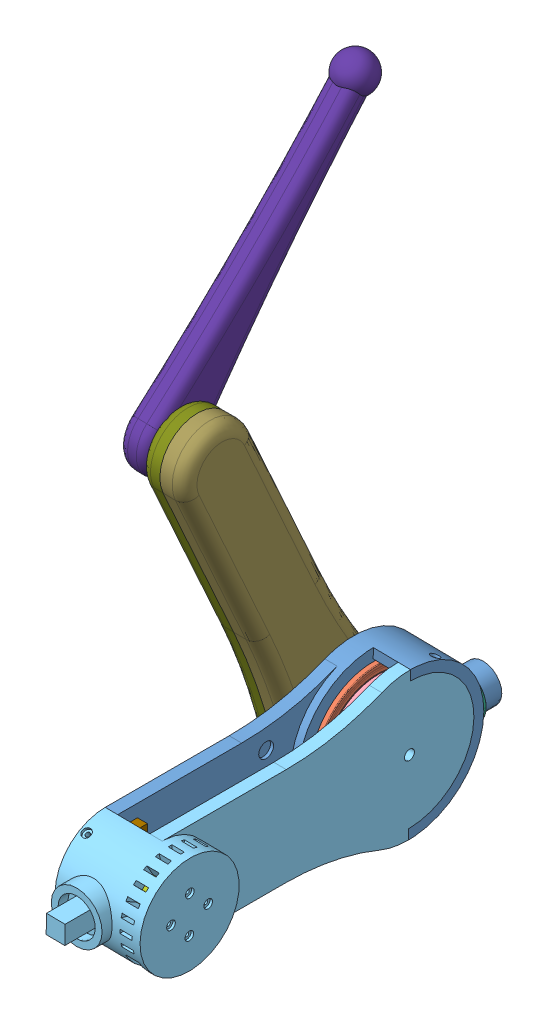
SolidWorks assembly upper leg + shoulder only, configuration Default. Lengths in mm.
Overall size (136.87 517.28 485.64).
29 component instances, 17 part files, 3 mates.
Components (placement in the parent):
- shoulder assembly-1: shoulder assembly [Default] at (18.7531 22.6608 5.5935) x (0.9999 -0.01415 0) z (0 0 1) size (72.6 146.54 345) (flexible)
  - body hip-1: body hip [Default] at (46.3831 172.9322 161.1274) size (46 120 310)
  - W_61816_2Z-1: W_61816_2Z [Default] at (56.3831 172.9322 161.1274) x (1 0 0) z (0 -0.196579 0.980488) size (10 124.5 124.5)
  - AXK_80105___AS_80105___AS_80105-1: AXK_80105___AS_80105___AS_80105 [Default] at (45.3831 172.9322 161.1274) size (6 105 105)
  - shoulder GT2 120-1: shoulder GT2 120 [Default] at (69.1831 172.9322 161.1274) x (0 0.418595 -0.908173) z (0 -0.908173 -0.418595) size (86 20 86)
  - body hip cover-2: body hip cover [Default] at (82.3831 172.9322 161.1274) size (68.6 120 317)
  - W_61706_2RZ-1: W_61706_2RZ [Default] at (71.8831 172.9322 101.1274) x (0 0 -1) z (0.9999 0.01415 0) size (4 46.12 46.12)
  - W_61706_2RZ-2: W_61706_2RZ [Default] at (82.3831 172.9322 161.1274) size (4 46.12 46.12)
  - MAD5008IPE-1: MAD5008IPE [Default] at (109.9831 172.9322 361.1274) x (0 1 0) z (0 0 1) size (56 29.3 56)
  - GT2 15 Teeth motor-1: GT2 15 Teeth motor [Default] at (82.5677 172.9322 361.1274) x (0 1 0) z (0 0 1) size (24 30 24)
  - hip joint encoder holder-1: hip joint encoder holder [Default] at (70.3831 172.9322 361.1274) x (0 -1 0) z (0 0 -1) size (80 8 46)
  - encoder-1: encoder [Default] at (62.6131 172.9322 361.1274) x (0 -0.992557 0.121778) z (-1 0 0) size (28.79 43.54 9.21)
  - W_617_8-1: W_617_8 [Default] at (53.8831 172.9322 361.1274) x (1 0 0) z (0 -0.003591 0.999994) size (2.5 14.75 14.75)
- lower leg assembly-1: lower leg assembly [Default] at (226.9258 314.1775 -50.1665) x (0.012851 0.908082 0.418595) z (-0.005923 -0.418553 0.908173) size (417.38 90.3 277.5) (flexible)
  - upper limb assembly-1: upper limb assembly [Default] at (-19.8745 -6.1915 12.8481) size (322.61 71.8 80) (flexible)
    - upper limb v4-1: upper limb v4 [Default] at (0.3187 172.8353 234.9828) size (320 47.8 80)
    - MAD5008IPE-1: MAD5008IPE [Default] at (0.3187 147.0353 234.9828) size (56 29.3 56)
    - GT2 15 Teeth motor-1: GT2 15 Teeth motor [Default] at (0.3187 174.4507 234.9828) size (24 30 24)
    - 15_45 pulley-1: 15_45 pulley [Default] at (100.957 199.9066 228.2835) x (-0.188791 0 0.982017) z (0.982017 0 0.188791) size (34 30.5 34)
    - W_617_8-1: W_617_8 [Default] at (109.9187 170.3353 234.9828) x (0 1 0) z (0.777212 0 0.629238) size (2.5 14.75 14.75)
    - W_61706_2RZ-1: W_61706_2RZ [Default] at (250.3187 174.3353 234.9828) x (0 -1 0) z (0.706264 0 0.707949) size (4 46.12 46.12)
    - encoder-1: encoder [Default] at (0.3187 191.6053 234.9828) x (0.325666 0 -0.945485) z (0 1 0) size (28.79 43.54 9.21)
    - encoder holder-1: encoder holder [Default] at (0.3187 182.8353 234.9828) x (0 0 -1) z (1 0 0) size (70 5 40.98)
    - knee joint 45T-1: knee joint 45T [Default] at (250.3187 183.8353 234.9828) x (0.418723 0 -0.908114) z (0.908114 0 0.418723) size (34 41.5 34)
    - upper limb cover v4-1: upper limb cover v4 [Default] at (0.3187 198.3353 234.9828) x (1 0 0) z (0 0 -1) size (320 15.79 80)
    - W_617_8-2: W_617_8 [Default] at (109.9187 198.3353 234.9828) x (0 1 0) z (0.777212 0 0.629238) size (2.5 14.75 14.75)
    - W_617_8-3: W_617_8 [Default] at (0.3187 198.3353 234.9828) x (0 1 0) z (0.914217 0 -0.405224) size (2.5 14.75 14.75)
    - W_61706_2RZ-2: W_61706_2RZ [Default] at (250.3187 200.8353 234.9828) x (0 -1 0) z (0.706264 0 0.707949) size (4 46.12 46.12)
  - lower limb-1: lower limb [Default] at (230.4442 205.6438 247.8309) x (0.908114 0 0.418723) z (0 -1 0) size (50 275 43.5)
Mates (geometry in assembly coordinates):
- Concentric1: concentric: cylinder of shoulder assembly-1/W_61816_2Z-1 through (127.5725 194.0704 166.7208) axis (0.9999 -0.01415 0) radius 40; cylinder of lower leg assembly-1/upper limb assembly-1/upper limb v4-1 through (43.581 195.259 166.7208) axis (0.9999 -0.01415 0) radius 40
- Concentric2: concentric: cylinder of shoulder assembly-1/shoulder GT2 120-1 through (87.9621 221.8789 179.2787) axis (0.9999 -0.01415 0) radius 1.7; cylinder of lower leg assembly-1/upper limb assembly-1/upper limb v4-1 through (85.7623 221.91 179.2787) axis (0.9999 -0.01415 0) radius 2.05
- Coincident1: coincident: plane of shoulder assembly-1/shoulder GT2 120-1 through (91.3762 194.5826 166.7208) normal (-0.9999 0.01415 0); plane of lower leg assembly-1/upper limb assembly-1/upper limb v4-1 through (91.3762 194.5826 166.7208) normal (0.9999 -0.01415 0)
